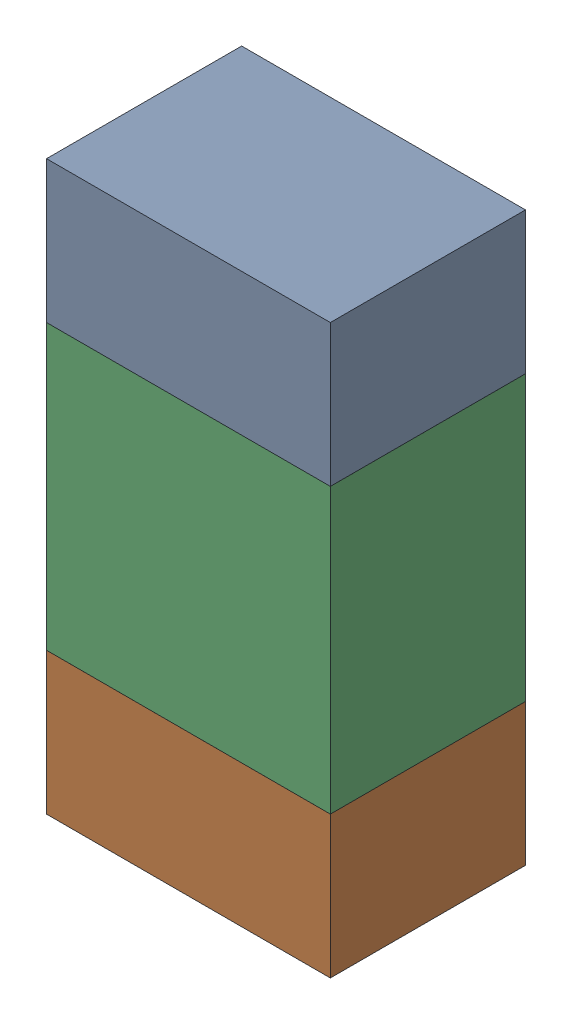
SolidWorks assembly R78, configuration ﾃﾞﾌｫﾙﾄ. Lengths in mm.
Overall size (0.8 1.6 0.55).
6 component instances, 2 part files, 0 mates.
Components (placement in the parent):
- 689261784-1: 689261784 [ﾃﾞﾌｫﾙﾄ] at (40.0001 69.5999 0) size (0.8 0.4 0.55)
  - Extruded_34-1: Extruded_34 [ﾃﾞﾌｫﾙﾄ] at origin size (0.8 0.4 0.55)
- 689261784-2: 689261784 [ﾃﾞﾌｫﾙﾄ] at (40.0001 68.3999 0) size (0.8 0.4 0.55)
  - Extruded_34-1: Extruded_34 [ﾃﾞﾌｫﾙﾄ] at origin size (0.8 0.4 0.55)
- 689261648-1: 689261648 [ﾃﾞﾌｫﾙﾄ] at (40.0001 69 0) size (0.8 0.8 0.55)
  - Extruded_33-1: Extruded_33 [ﾃﾞﾌｫﾙﾄ] at origin size (0.8 0.8 0.55)
